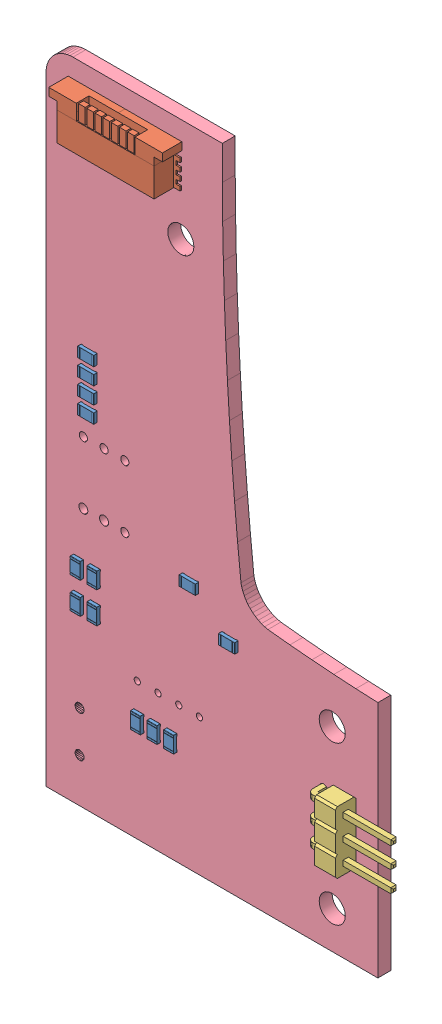
SolidWorks assembly Controller_body, configuration 默认. Lengths in mm.
Overall size (44.02 78.99 5.56).
32 component instances, 4 part files, 0 mates.
Components (placement in the parent):
- Controller_body.step-1: Controller_body.step [默认] at origin size (44.02 78.99 5.56)
  - R_0805_2012Metric.step-1: R_0805_2012Metric.step [默认] at (97.536 -98.298 1.63) x (-1 0 0) z (0 0 1) size (2 1.2 0.45)
    - SOLID.step-1: SOLID.step [默认] at origin size (2 1.2 0.45)
  - R_0805_2012Metric.step-2: R_0805_2012Metric.step [默认] at (85.106 -86.36 1.63) x (-1 0 0) z (0 0 1) size (2 1.2 0.45)
    - SOLID.step-1: SOLID.step [默认] at origin size (2 1.2 0.45)
  - TE_84953-6_1x06-1MP_P1.0mm_Horizontal.step-1: TE_84953-6_1x06-1MP_P1.0mm_Horizontal.step [默认] at (89.662 -56.46 1.63) x (-1 0 0) z (0 0 1) size (13.92 6.54 2.56)
    - SOLID-0.step-1: SOLID-0.step [默认] at origin size (13.92 6.54 2.56)
  - R_0805_2012Metric.step-3: R_0805_2012Metric.step [默认] at (83.82 -107.188 1.63) x (0 1 0) z (0 0 1) size (2 1.2 0.45)
    - SOLID.step-1: SOLID.step [默认] at origin size (2 1.2 0.45)
  - R_0805_2012Metric.step-4: R_0805_2012Metric.step [默认] at (102.362 -102.108 1.63) size (2 1.2 0.45)
    - SOLID.step-1: SOLID.step [默认] at origin size (2 1.2 0.45)
  - R_0805_2012Metric.step-5: R_0805_2012Metric.step [默认] at (93.218 -116.078 1.63) x (0 1 0) z (0 0 1) size (2 1.2 0.45)
    - SOLID.step-1: SOLID.step [默认] at origin size (2 1.2 0.45)
  - R_0805_2012Metric.step-6: R_0805_2012Metric.step [默认] at (85.106 -82.296 1.63) x (-1 0 0) z (0 0 1) size (2 1.2 0.45)
    - SOLID.step-1: SOLID.step [默认] at origin size (2 1.2 0.45)
  - R_0805_2012Metric.step-7: R_0805_2012Metric.step [默认] at (85.106 -84.328 1.63) x (-1 0 0) z (0 0 1) size (2 1.2 0.45)
    - SOLID.step-1: SOLID.step [默认] at origin size (2 1.2 0.45)
  - PinHeader_1x03_P2.54mm_Horizontal.step-1: PinHeader_1x03_P2.54mm_Horizontal.step [默认] at (113.735 -112.014 1.63) size (10.36 7.62 5.54)
    - SOLID-1.step-1: SOLID-1.step [默认] at origin size (10.36 7.62 5.54)
  - R_0805_2012Metric.step-8: R_0805_2012Metric.step [默认] at (85.852 -103.362 1.63) x (0 -1 0) z (0 0 1) size (2 1.2 0.45)
    - SOLID.step-1: SOLID.step [默认] at origin size (2 1.2 0.45)
  - R_0805_2012Metric.step-9: R_0805_2012Metric.step [默认] at (95.25 -116.078 1.63) x (0 1 0) z (0 0 1) size (2 1.2 0.45)
    - SOLID.step-1: SOLID.step [默认] at origin size (2 1.2 0.45)
  - R_0805_2012Metric.step-10: R_0805_2012Metric.step [默认] at (85.106 -80.264 1.63) x (-1 0 0) z (0 0 1) size (2 1.2 0.45)
    - SOLID.step-1: SOLID.step [默认] at origin size (2 1.2 0.45)
  - R_0805_2012Metric.step-11: R_0805_2012Metric.step [默认] at (91.186 -116.078 1.63) x (0 1 0) z (0 0 1) size (2 1.2 0.45)
    - SOLID.step-1: SOLID.step [默认] at origin size (2 1.2 0.45)
  - R_0805_2012Metric.step-12: R_0805_2012Metric.step [默认] at (83.82 -103.362 1.63) x (0 -1 0) z (0 0 1) size (2 1.2 0.45)
    - SOLID.step-1: SOLID.step [默认] at origin size (2 1.2 0.45)
  - R_0805_2012Metric.step-13: R_0805_2012Metric.step [默认] at (85.852 -107.188 1.63) x (0 1 0) z (0 0 1) size (2 1.2 0.45)
    - SOLID.step-1: SOLID.step [默认] at origin size (2 1.2 0.45)
  - PCB.step-1: PCB.step [默认] at origin size (40.64 78.99 1.58)
